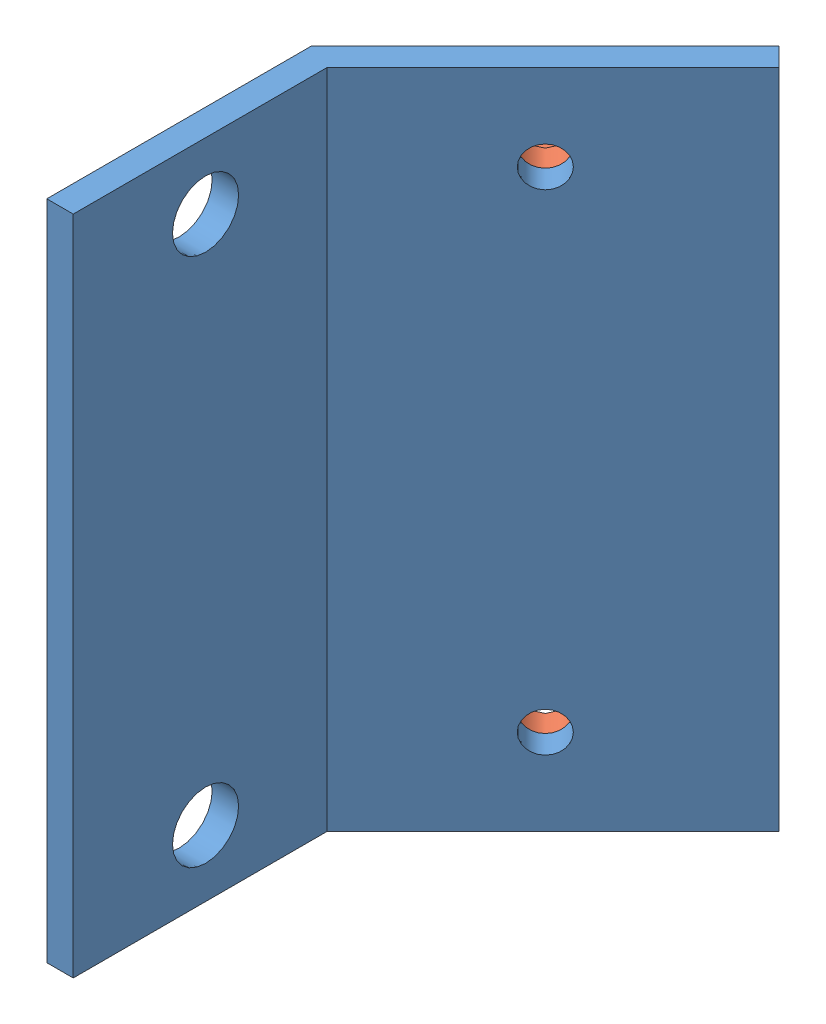
SolidWorks assembly test_porte_capteur_1, configuration Défaut. Lengths in mm.
Overall size (31.5 50 46.55).
2 component instances, 2 part files, 3 mates.
Components (placement in the parent):
- Attache_A45_L50_h50-1: Attache_A45_L50_h50 [Défaut] at (-17.7797 -5.8574 0) size (19.09 50 37.68)
- GP2D12-1: GP2D12 [Default] at (-15.623 4.3926 -22.1567) x (0 1 0) z (-0.707107 0 0.707107) size (44.5 15.6 23.9)
Mates (geometry in assembly coordinates):
- Coaxiale1: concentric: cylinder of Attache_A45_L50_h50-1; cylinder of ?
- Coaxiale2: concentric: cylinder of Attache_A45_L50_h50-1; cylinder of ?
- Coïncidente1: coincident anti-aligned: plane of ? through (-8.0927 4.3926 -14.6264) normal (-0.707107 0 -0.707107); plane of Attache_A45_L50_h50-1 through (-17.7797 44.1426 -20) normal (-0.707107 0 -0.707107)
